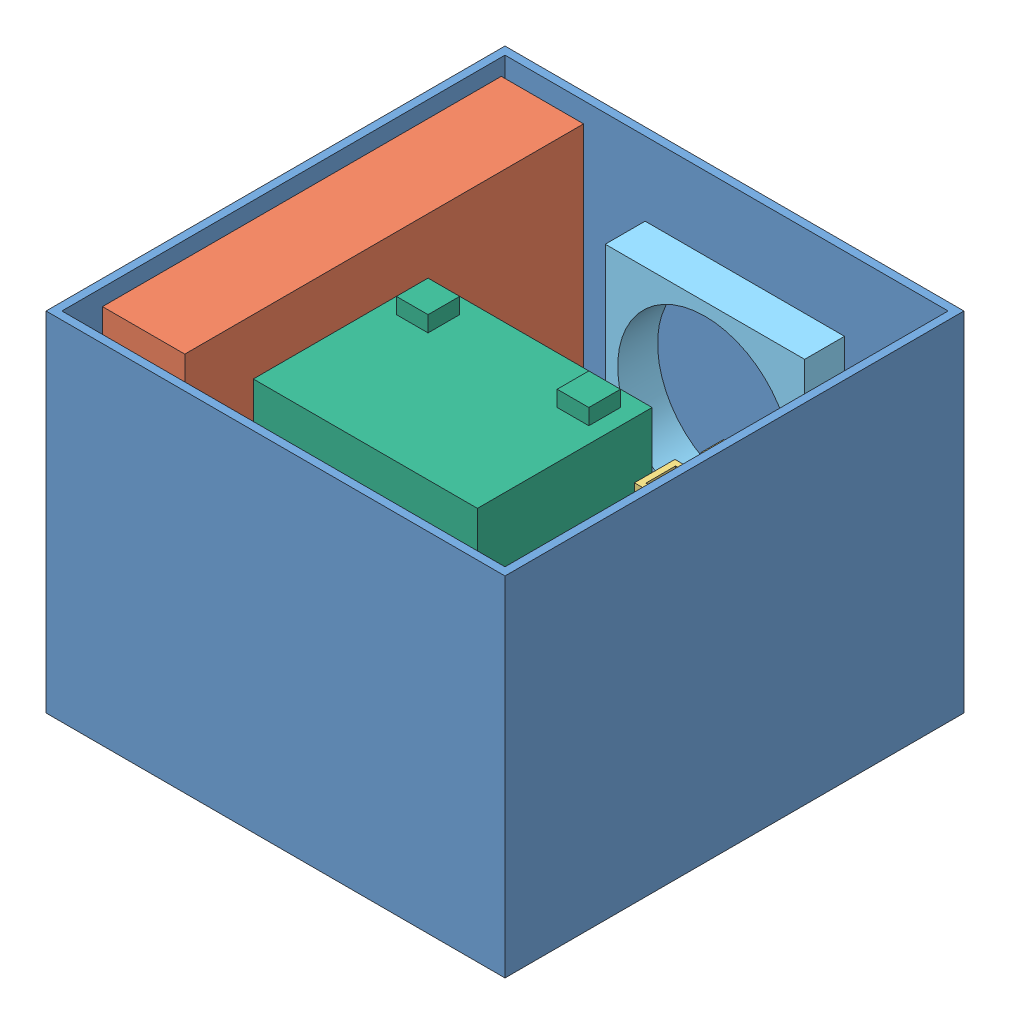
SolidWorks assembly station, configuration Default. Lengths in mm.
Overall size (184.15 140.22 258.26).
6 component instances, 6 part files, 10 mates.
Components (placement in the parent):
- chasis-1: chasis [Default] at (36.8371 31.4555 162.1975) size (184.15 139.7 184.15)
- router_body-1: router_body [Default] at (-11.903 108.174 161.9349) x (0 0 1) z (0 -1 0) size (160.02 33.02 127)
- BEAGLEBONE_BLACK-1: BEAGLEBONE_BLACK [Default] at (112.5017 144.7902 134.122) x (0 -1 0) z (-1 0 0) size (90.45 54.66 19.4)
- xbeePro900-1: xbeePro900 [Default] at (108.0984 79.1775 122.6234) x (0 1 0) z (0 0 1) size (24.38 9.95 32.94)
- 80mmFan-1: 80mmFan [Default] at (45.2004 102.6077 74.3344) x (1 0 0) z (0 -1 0) size (80 16 80)
- battery1250-1: battery1250 [Default] at (44.1901 59.3257 190.5248) x (-1 0 0) z (0 0 -1) size (89.92 107.44 70.1)
Mates (geometry in assembly coordinates):
- Parallel1: parallel anti-aligned: plane of chasis-1 through (-52.0629 37.8055 73.2975) normal (1 0 0); plane of router_body-1 through (-44.923 108.174 161.9349) normal (-1 0 0)
- Parallel2: parallel anti-aligned: plane of chasis-1 through (36.8371 37.8055 162.1975) normal (0 1 0); plane of router_body-1 through (-44.923 44.674 81.9249) normal (0 -1 0)
- Parallel4: parallel anti-aligned: plane of chasis-1 through (125.7371 37.8055 73.2975) normal (-1 0 0); plane of BEAGLEBONE_BLACK-1 through (114.0765 144.8129 140.472) normal (1 0 0)
- Parallel3: parallel anti-aligned: plane of chasis-1 through (36.8371 37.8055 162.1975) normal (0 1 0); plane of BEAGLEBONE_BLACK-1 through (181.3865 58.4054 146.822) normal (0 -1 0)
- Parallel5: parallel anti-aligned: plane of chasis-1 through (125.7371 37.8055 73.2975) normal (-1 0 0); plane of xbeePro900-1 through (109.978 79.1775 122.6234) normal (1 0 0)
- Parallel6: parallel aligned: plane of chasis-1 through (36.8371 37.8055 162.1975) normal (0 1 0); plane of xbeePro900-1 through (107.2856 103.5615 122.6234) normal (0 1 0)
- Parallel7: parallel anti-aligned: plane of chasis-1 through (-52.0629 37.8055 73.2975) normal (0 0 1); plane of 80mmFan-1 through (45.2004 102.6077 74.3344) normal (0 0 -1)
- Parallel8: parallel anti-aligned: plane of chasis-1 through (125.7371 37.8055 73.2975) normal (-1 0 0); plane of 80mmFan-1 through (85.2004 142.6077 90.3344) normal (1 0 0)
- Parallel11: parallel anti-aligned: plane of chasis-1 through (-52.0629 37.8055 251.0975) normal (0 0 -1); plane of battery1250-1 through (89.1481 160.4177 225.5768) normal (0 0 1)
- Parallel12: parallel anti-aligned: plane of chasis-1 through (125.7371 37.8055 73.2975) normal (-1 0 0); plane of battery1250-1 through (89.1481 160.4177 155.4728) normal (1 0 0)
